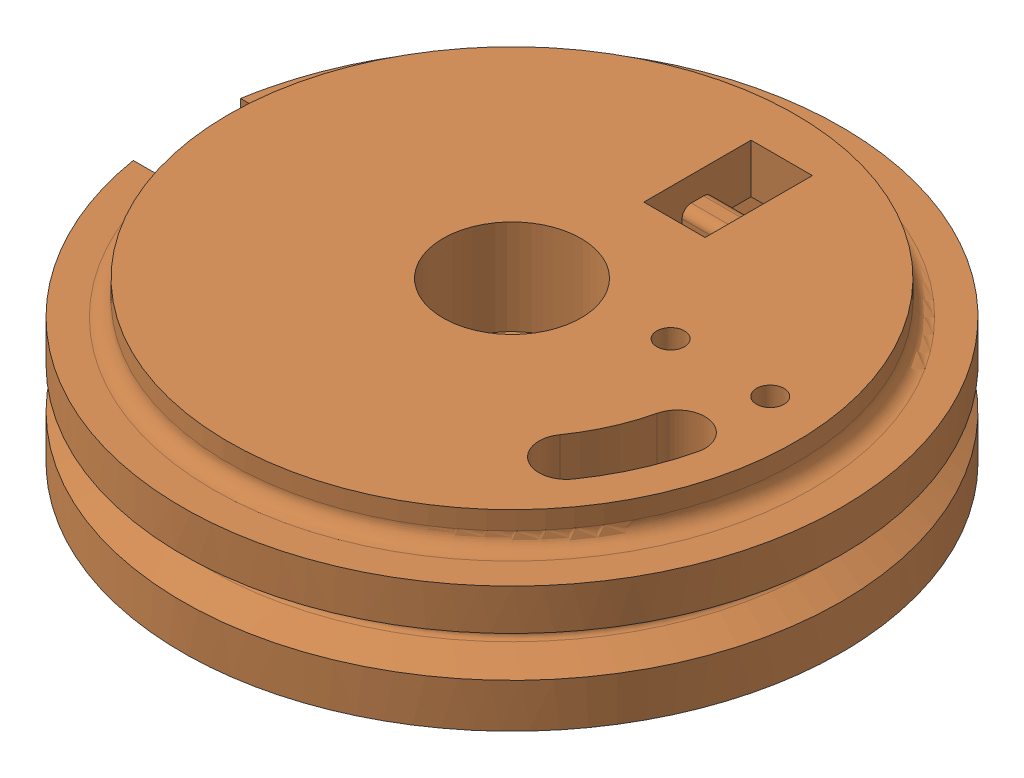
SolidWorks assembly floating_half_pulley_with_insert, configuration Default. Lengths in mm.
Overall size (42.72 10.4 43).
2 component instances, 2 part files, 0 mates.
Components (placement in the parent):
- m3_heat_set_insert_94180A331_94180A331-1: m3_heat_set_insert_94180A331_94180A331 [Default] at (0 4.8 26.7112) x (0 -0.064302 0.99793) z (0 -0.99793 -0.064302) size (5.56 3.88 5.56)
- half-pulley_Floating Half Pulley Underside-1: half-pulley_Floating Half Pulley Underside [Default] at (19.6031 8.8 26.7112) x (1 0 0) z (0 0 -1) size (42.72 10.4 43)
